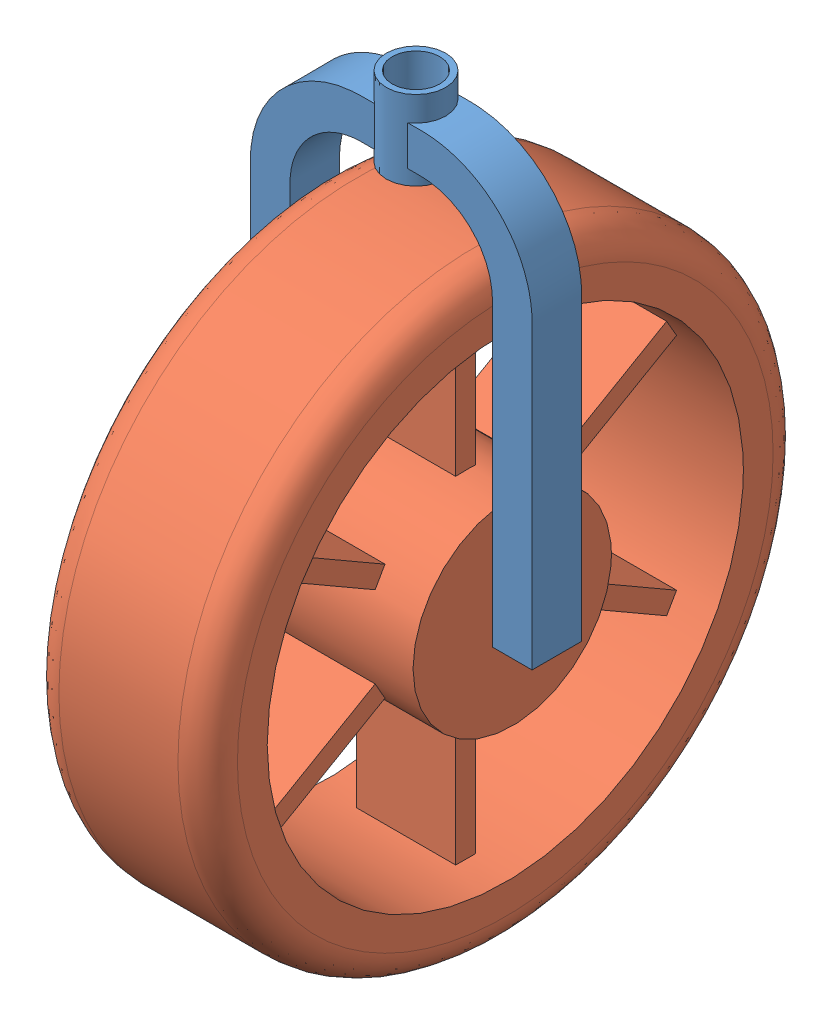
SolidWorks assembly Assem1, configuration Default. Lengths in mm.
Overall size (142.03 362 300).
2 component instances, 2 part files, 6 mates.
Components (placement in the parent):
- Chave_Motor-1: Chave_Motor [Default] at origin size (142.03 220 30)
- Motor_Roda-2: Motor_Roda [Default] x (0 0 -1) z (1 0 0) size (300 300 97)
Mates (geometry in assembly coordinates):
- Coincident1: coincident: plane of Chave_Motor-1 through (0 0 0) normal (1 0 0); plane of Motor_Roda-2 through (0 0 0) normal (1 0 0)
- Coincident3: coincident: plane of Chave_Motor-1 through (0 0 0) normal (0 0 1); plane of Motor_Roda-2 through (0 0 0) normal (0 0 -1)
- Coincident4: coincident: plane of Chave_Motor-1 through (0 0 0) normal (0 1 0); plane of Motor_Roda-2 through (0 0 0) normal (0 1 0)
- Coincident5: coincident: plane of Chave_Motor-1 through (0 0 0) normal (0 0 1); plane of assembly through (0 0 0) normal (0 0 1)
- Coincident6: coincident: plane of Chave_Motor-1 through (0 0 0) normal (1 0 0); plane of assembly through (0 0 0) normal (1 0 0)
- Coincident7: coincident: plane of Chave_Motor-1 through (0 0 0) normal (0 1 0); plane of assembly through (0 0 0) normal (0 1 0)
